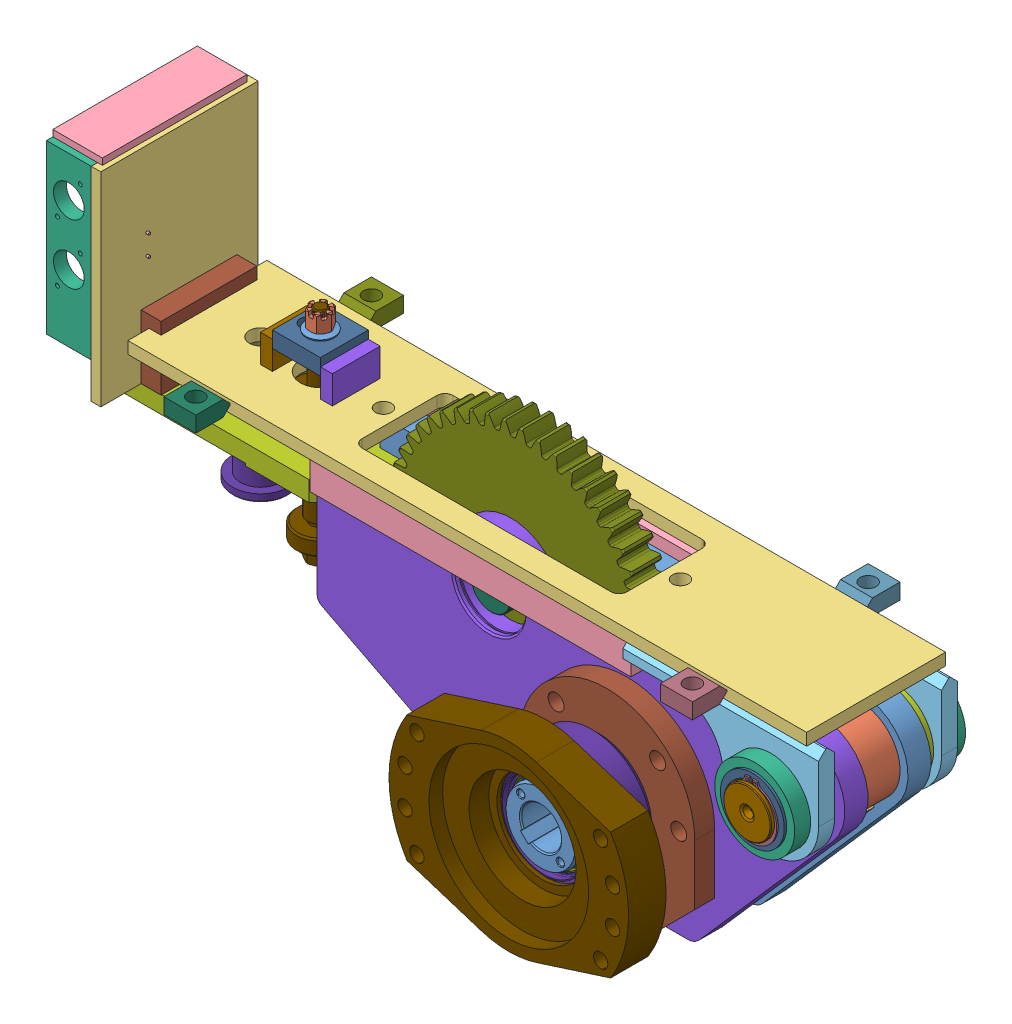
SolidWorks assembly g1_3_1_1, configuration 默认. Lengths in mm.
Overall size (943 530 331.8).
108 component instances, 72 part files, 63 mates.
Components (placement in the parent):
- g1_3_1_1_5_1-1: g1_3_1_1_5_1 [默认] at (343.3203 -95 30) x (-1 0 0) z (0 1 0) size (926 108 318.6)
  - g1_3_1_1_5-1_af1_1-1: g1_3_1_1_5-1_af1_1 [默认] at origin size (661 29 318.6)
  - g1_3_1_1_5-2_af0_1-1: g1_3_1_1_5-2_af0_1 [默认] at (-213.2 29 0) size (100 50 100)
  - g1_3_1_1_5-4_1-1: g1_3_1_1_5-4_1 [默认] at (-149.9151 54 -132.7301) x (0 1 0) z (-0.659692 0 0.751536) size (50 10 223)
  - g1_3_1_1_5-5_1-1: g1_3_1_1_5-5_1 [默认] at (20.5 54 -217) x (1 0 0) z (0 1 0) size (194 10 50)
  - g1_3_1_1_5-6_1-1: g1_3_1_1_5-6_1 [默认] at (248.4498 54 -161.5242) x (0 1 0) z (0.890083 0 0.455798) size (50 10 284)
  - g1_3_1_1_5-7_1-1: g1_3_1_1_5-7_1 [默认] at (377.8 54 -43.9) x (0 0 -1) z (0 1 0) size (87 10 50)
  - g1_3_1_1_5-9_af0_1-1: g1_3_1_1_5-9_af0_1 [默认] at (502.8 54 24.6) x (1 0 0) z (0 1 0) size (300 25 108)
  - g1_3_1_1_5-1_af0_1-1: g1_3_1_1_5-1_af0_1 [默认] at (0 79 0) size (661 29 318.6)
- g1_3_1_1_4_1-1: g1_3_1_1_4_1 [默认] at (556.5203 -95 -33.3) x (1 0 0) z (0 -1 0) size (80 234 80)
  - g1_3_1_1_4-1_1-1: g1_3_1_1_4-1_1 [默认] at origin size (60 234 60.04)
  - g1_3_1_1_4-3_1-2: g1_3_1_1_4-3_1 [默认] at (0 224.3 0) size (80 3 80)
  - g1_3_1_1_4-2_1-1: g1_3_1_1_4-2_1 [默认] at (0 174.3 0) size (72 50 72)
  - g1_3_1_1_4-2_1-2: g1_3_1_1_4-2_1 [默认] at (0 9.7 0) size (72 50 72)
  - g1_3_1_1_4-2_1-3: g1_3_1_1_4-2_1 [默认] at (0 62.7 0) size (72 50 72)
  - g1_3_1_1_4-2_1-4: g1_3_1_1_4-2_1 [默认] at (0 121.3 0) size (72 50 72)
- g1_3_1_1_2_1-1: g1_3_1_1_2_1 [默认] at (343.3203 -195.4 0) x (1 0.000801 0) z (0.000801 -1 0) size (219.6 152 245)
  - g1_3_1_1_2-1_1-1: g1_3_1_1_2-1_1 [默认] at origin size (219.6 61 245)
  - g1_3_1_1_2-2_1-1: g1_3_1_1_2-2_1 [默认] at (0 152 0) x (-0.047609 0 0.998866) z (0 1 0) size (120.16 120.16 117)
  - g1_3_1_1_2-3_1-1: g1_3_1_1_2-3_1 [默认] at (-20.1525 129 20.1525) x (0 -1 0) z (0.707107 0 0.707107) size (28 11 14)
- g1_3_1_1_3_1-1: g1_3_1_1_3_1 [默认] at (170.5203 -78.4 83.75) x (0 0 -1) z (-0.004458 0.99999 0) size (103.5 321.87 322.01)
  - g1_3_1_1_3-1_1-1: g1_3_1_1_3-1_1 [默认] at origin size (103.5 52 52)
  - _X2_60F08F6E_X0_g1_3_1_1_3-2_1-1: _X2_60F08F6E_X0_g1_3_1_1_3-2_1 [默认] at (25 0 0) x (0 0 1) z (1 0 0) size (322.01 321.87 50.08)
- g1_3_1_1_1_2-1: g1_3_1_1_1_2 [默认] at (343.3203 -195.4 123.8) x (1 0.000801 0) z (0.000801 -1 0) size (300 165.8 228)
  - g1_3_1_1_1_1_1-1: g1_3_1_1_1_1_1 [默认] at origin size (300 112 228)
    - g1_3_1_1_1_1-2_af0_1-1: g1_3_1_1_1_1-2_af0_1 [默认] at (0 50 0) size (150 65 150)
    - g1_3_1_1_1_1-3_af0_1-1: g1_3_1_1_1_1-3_af0_1 [默认] at (0 140 0) size (300 47 228)
  - g1_3_1_1_1-2_1-1: g1_3_1_1_1-2_1 [默认] at (0 122.2 0) x (0.707107 0 0.707107) z (0.707107 0 -0.707107) size (90 126 90)
  - 80_gb894_1_1-1: 80_gb894_1_1 [默认] at (-2.4 11.1 -38.1746) x (1 0 0) z (0 -1 0) size (85.83 90.87 2.5)
- g1_3_1_1_6_1-1: g1_3_1_1_6_1 [默认] at (170.5203 0 84) x (-1 0 0) z (0 0 1) size (875 200 260)
  - g1_3_1_1_6-4_af0_1-1: g1_3_1_1_6-4_af0_1 [默认] at origin size (850 15 174)
  - g1_3_1_1_6-8_1-1: g1_3_1_1_6-8_1 [默认] at (0 40 57) x (1 0 0) z (0 -1 0) size (402 20 44.8)
  - g1_3_1_1_6-8_1-2: g1_3_1_1_6-8_1 [默认] at (0 40 -77) x (1 0 0) z (0 -1 0) size (402 20 44.8)
  - g1_3_1_1_6-1_1-1: g1_3_1_1_6-1_1 [默认] at (-386 95 -87) x (1 0 0) z (0 -1 0) size (245 20 140)
  - g1_3_1_1_6-1_1-2: g1_3_1_1_6-1_1 [默认] at (-386 95 67) x (1 0 0) z (0 -1 0) size (245 20 140)
  - g1_3_1_1_6-3_1-1: g1_3_1_1_6-3_1 [默认] at (-386 95 87) x (-1 0 0) z (0 1 0) size (100 20 100)
  - g1_3_1_1_6-3_1-2: g1_3_1_1_6-3_1 [默认] at (-386 95 -107) x (-1 0 0) z (0 1 0) size (100 20 100)
  - g1_3_1_1_6-2_1-1: g1_3_1_1_6-2_1 [默认] at (-386 95 57) x (-1 0 0) z (0 1 0) size (100 10 100)
  - g1_3_1_1_6-2_1-2: g1_3_1_1_6-2_1 [默认] at (-386 95 -57) x (1 0 0) z (0 1 0) size (100 10 100)
  - g1_3_1_1_6-9_1-1: g1_3_1_1_6-9_1 [默认] at (220 -17 0) x (0 1 0) z (0 0 -1) size (35 15 60)
  - g1_3_1_1_6-9_af0_1-1: g1_3_1_1_6-9_af0_1 [默认] at (310 -17 0) x (0 1 0) z (0 0 1) size (35 15 60)
  - g1_3_1_1_6-10_1-1: g1_3_1_1_6-10_1 [默认] at (265 -45 0) size (60 20 60)
  - g1_3_1_1_6-12_af0_1-1: g1_3_1_1_6-12_af0_1 [默认] at (434 25 0.5) x (0 0 1) z (0 -1 0) size (120 25 80)
  - g1_3_1_1_6-11_af0_1-1: g1_3_1_1_6-11_af0_1 [默认] at (357 15 0) size (94 40 60)
  - g1_3_1_1_6-5_af0_1-1: g1_3_1_1_6-5_af0_1 [默认] at (-311 -5 108.5) x (0 0 -1) z (1 0 0) size (43 19.6 40)
  - g1_3_1_1_6-5_af1_1-1: g1_3_1_1_6-5_af1_1 [默认] at (-311 -5 -108.5) x (0 0 1) z (-1 0 0) size (43 19.6 40)
  - g1_3_1_1_6-5_af2_1-1: g1_3_1_1_6-5_af2_1 [默认] at (311 -5 108.5) x (0 0 -1) z (1 0 0) size (43 19.6 40)
  - g1_3_1_1_6-5_af3_1-1: g1_3_1_1_6-5_af3_1 [默认] at (311 -5 -108.5) x (0 0 1) z (-1 0 0) size (43 19.6 40)
- g1_3_1_1-1_1-1: g1_3_1_1-1_1 [默认] at (-169.4797 -45.5 84) x (1 0 -0.00083) z (-0.00083 0 -1) size (70 135 70)
- g1_3_1_1_7_1-1: g1_3_1_1_7_1 [默认] at (-94.4797 -16.0167 84) x (0 1 0) z (0.020278 0 0.999794) size (272.02 60 60)
  - g1_3_1_1_7-1_1-1: g1_3_1_1_7-1_1 [默认] at origin size (272.02 60 60)
  - a35_5_gb1972_1-1: a35_5_gb1972_1 [默认] at (39.2167 0 0) x (0 0.075145 0.997173) z (0 0.997173 -0.075145) size (35.5 7.2 35.5)
  - a35_5_gb1972_1-2: a35_5_gb1972_1 [默认] at (62.8167 0 0) x (0 -0.99777 0.066751) z (0 -0.066751 -0.99777) size (35.5 7.2 35.5)
  - m16a_gb6178_1-1: m16a_gb6178_1 [默认] at (85.8167 13.8564 0) x (0 -1 0) z (-1 0 0) size (27.71 24 20.8)
- g1_3_1_1_8_1-1: g1_3_1_1_8_1 [默认] at (-258.4797 62.5 96.5) x (0 0 -1) z (0 1 0) size (197 71 268.3)
  - g1_3_1_1_8_1_af0_1-1: g1_3_1_1_8_1_af0_1 [默认] at origin size (197 68 263)
    - g1_3_1_1_8_1-3_af1_1-1: g1_3_1_1_8_1-3_af1_1 [默认] at origin size (197 12 255)
    - g1_3_1_1_8_1-1_1-1: g1_3_1_1_8_1-1_1 [默认] at (0 37 127.5) x (1 0 0) z (0 -1 0) size (181 8 62)
    - g1_3_1_1_8_1-2_af1_1-1: g1_3_1_1_8_1-2_af1_1 [默认] at (98.5 40 22.5) x (0 1 0) z (0 0 1) size (56 16 210)
    - g1_3_1_1_8_1-2_af0_1-1: g1_3_1_1_8_1-2_af0_1 [默认] at (-98.5 40 22.5) x (0 1 0) z (0 0 -1) size (56 16 210)
    - g1_3_1_1_8_1-5_1-1: g1_3_1_1_8_1-5_1 [默认] at (0 40 -82.5) x (1 0 0) z (0 1 0) size (165 8 56)
    - g1_3_1_1_8_1-6_1-1: g1_3_1_1_8_1-6_1 [默认] at (27.5 40 -106) x (0 1 0) z (0 0 -1) size (56 6 31)
    - g1_3_1_1_8_1-6_1-2: g1_3_1_1_8_1-6_1 [默认] at (-8.5 40 -106) x (0 1 0) z (0 0 -1) size (56 6 31)
    - g1_3_1_1_8_1-4_af1_1-1: g1_3_1_1_8_1-4_af1_1 [默认] at (-10 12 5) size (105 17 85)
    - g1_3_1_1_8_1-8_af0_1-1: g1_3_1_1_8_1-8_af0_1 [默认] at (12.5 40 -127.5) x (0 1 0) z (1 0 0) size (56 6 54)
  - g1_3_1_1_8-3_1-1: g1_3_1_1_8-3_1 [默认] at (12.5 37 -32.7987) x (0 0 -1) z (0 1 0) size (229 15 15)
  - g1_3_1_1_8-6_1-1: g1_3_1_1_8-6_1 [默认] at (12.5 37 30.1) x (-1 0 0) z (0 1 0) size (26 60 26)
  - g1_3_1_1_8-5_1-1: g1_3_1_1_8-5_1 [默认] at (12.5 29 -27.5) size (60 24 20)
  - g1_3_1_1_8-9_af0_1-1: g1_3_1_1_8-9_af0_1 [默认] at (-42.5 17 5.5) size (34 10 74)
  - g1_3_1_1_8-10_1-1: g1_3_1_1_8-10_1 [默认] at (12.5 37 -127.5) x (1 0 0) z (0 1 0) size (40 2 32)
  - ya2x20x90-2_gb2089_af0_1-1: ya2x20x90-2_gb2089_af0_1 [默认] at (12.5 37 -82.5) x (0 0 -1) z (1 0 0) size (92.3 24.62 24.71)
  - 14x2_65_gb3452_1_1-1: 14x2_65_gb3452_1_1 [默认] at (12.5 37 -124.5) x (0 0 1) z (0 1 0) size (2.65 19.38 19.38)
  - 15_gb894_1_1-1: 15_gb894_1_1 [默认] at (12 29.8675 -73.9) size (17.18 18.67 1.11)
  - 8_gb93_1-1: 8_gb93_1 [默认] at (32.5 53 -27.5) x (-1 0 0) z (0 1 0) size (12.3 12.3 2.1)
  - m8x40_gb5782_1-1: m8x40_gb5782_1 [默认] at (32.5 55.1 -27.5) size (15.01 45.3 13)
  - 8_gb93_1-2: 8_gb93_1 [默认] at (-7.5 53 -27.5) x (-1 0 0) z (0 1 0) size (12.3 12.3 2.1)
  - m8x40_gb5782_1-2: m8x40_gb5782_1 [默认] at (-7.5 55.1 -27.5) size (15.01 45.3 13)
  - m3x10_gb818_1-1: m3x10_gb818_1 [默认] at (57.5 2 60.5) size (5.81 12.5 5.77)
  - m3x10_gb818_1-2: m3x10_gb818_1 [默认] at (57.5 2 100.5) size (5.81 12.5 5.77)
  - m3x10_gb818_1-3: m3x10_gb818_1 [默认] at (-17.5 2 100.5) size (5.81 12.5 5.77)
  - m3x10_gb818_1-4: m3x10_gb818_1 [默认] at (-57.5 2 100.5) size (5.81 12.5 5.77)
  - m3x30_gb818_1-1: m3x30_gb818_1 [默认] at (-40.5 -3 7.5) size (5.81 32.5 5.77)
  - m3x30_gb818_1-2: m3x30_gb818_1 [默认] at (-40.5 -3 32.9) size (5.81 32.5 5.77)
  - 6_gb93_1-9: 6_gb93_1 [默认] at (-52.5 28.6 -17.5) x (1 0 0) z (0 -1 0) size (9.3 9.3 1.6)
  - m6x20_gb5783_1-9: m6x20_gb5783_1 [默认] at (-52.5 28.6 -17.5) size (11.55 24 10)
  - 6_gb93_1-10: 6_gb93_1 [默认] at (-32.5 28.6 -17.5) x (1 0 0) z (0 -1 0) size (9.3 9.3 1.6)
  - m6x20_gb5783_1-10: m6x20_gb5783_1 [默认] at (-32.5 28.6 -17.5) size (11.55 24 10)
  - 5x14_gb119_2_1-1: 5x14_gb119_2_1 [默认] at (-42.5 27 -3.5) size (5 14 5)
  - m3x6_gb818_1-1: m3x6_gb818_1 [默认] at (27.5 37 -123.5) x (1 0 0) z (0 1 0) size (5.81 8.5 5.77)
  - m3x6_gb818_1-2: m3x6_gb818_1 [默认] at (-2.5 37 -123.5) x (1 0 0) z (0 1 0) size (5.81 8.5 5.77)
- _X2_57AB5708_X0_16_gb93_1-9: _X2_57AB5708_X0_16_gb93_1 [默认] at (-270.4797 -50 44) x (0 0.924225 0.381849) z (-1 0 0) size (24.4 24.4 4.1)
- _X2_87BA6813_X0_m16x35_gb5783_10_1-1: _X2_87BA6813_X0_m16x35_gb5783_10_1 [默认] at (-274.5797 -50 44) x (0 -0.866025 -0.5) z (0 0.5 -0.866025) size (27.71 45 24)
- _X2_57AB5708_X0_16_gb93_1-10: _X2_57AB5708_X0_16_gb93_1 [默认] at (-270.4797 -50 124) x (0 0.924225 0.381849) z (-1 0 0) size (24.4 24.4 4.1)
- _X2_87BA6813_X0_m16x35_gb5783_10_1-2: _X2_87BA6813_X0_m16x35_gb5783_10_1 [默认] at (-274.5797 -50 124) x (0 -0.866025 -0.5) z (0 0.5 -0.866025) size (27.71 45 24)
- g1_3_1_1_1_1-1_af0_1-1: g1_3_1_1_1_1-1_af0_1 [默认] at (343.3203 -195.4 113) x (1 0 0) z (0 -1 0) size (220 42 245)
- g1_3_1_1_7-2_1-1: g1_3_1_1_7-2_1 [默认] at (-126.2339 -95.4 83.9778) x (1 0 0.0007) z (0 -1 0) size (63.51 55 25)
- g1_3_1_1_4-3_1-2: g1_3_1_1_4-3_1 [默认] at (556.5203 -95 -23.6) x (-0.923728 -0.383049 0) z (0.383049 -0.923728 0) size (80 3 80)
- 60_gb894_1_1-2: 60_gb894_1_1 [默认] at (558.4703 -66.5668 -28.6) x (-1 0 0) z (0 0 1) size (65.16 69.76 2)
- 60_gb894_1_1-3: 60_gb894_1_1 [默认] at (558.4703 -66.5668 194) x (-1 0 0) z (0 0 1) size (65.16 69.76 2)
- 16x10x45_gb1096_1-2: 16x10x45_gb1096_1 [默认] at (170.4089 -53.4002 83.25) x (0 0 -1) z (0.004458 -0.99999 0) size (45 16 10)
- g1_3_1_1_1-1_1-1: g1_3_1_1_1-1_1 [默认] at (343.3203 -195.4 210.3) x (0 0 -1) z (0.990882 0.134732 0) size (20 110 110)
- b90x110x12_gb9877_1_rubber_1-1: b90x110x12_gb9877_1_rubber_1 [默认] at (343.3203 -195.4 194.3) x (1 0 0) z (0 -1 0) size (108.6 12 108.6)
- b90x110x12_gb9877_1_rubber_1-2: b90x110x12_gb9877_1_rubber_1 [默认] at (343.3203 -195.4 226.3) x (1 0 0) z (0 1 0) size (108.6 12 108.6)
- b90x110x12_gb9877_1_frame_1-1: b90x110x12_gb9877_1_frame_1 [默认] at (343.3203 -195.4 232.3) x (-0.923728 -0.383049 0) z (-0.383049 0.923728 0) size (107.2 9.5 107.2)
- b90x110x12_gb9877_1_frame_1-2: b90x110x12_gb9877_1_frame_1 [默认] at (343.3203 -195.4 188.3) x (0.999991 -0.004354 0) z (0.004354 0.999991 0) size (107.2 9.5 107.2)
- g1_3_1_1_5-8_1-1: g1_3_1_1_5-8_1 [默认] at (-94.4797 -70.4 84) x (0.999971 0 -0.007558) z (0.007558 0 0.999971) size (60 50 60)
- 15_gb894_1_1-1: 15_gb894_1_1 [默认] at (-302.5811 152.7 83.1678) x (-0.046648 0 0.998911) z (0 1 0) size (17.18 18.67 1.11)
- 15_gb894_1_1-2: 15_gb894_1_1 [默认] at (-302.6048 91.5 83.404) x (-0.01346 0 0.999909) z (0 1 0) size (17.18 18.67 1.11)
Mates (geometry in assembly coordinates):
- 重合1: coincident anti-aligned: plane of g1_3_1_1_2_1-1/g1_3_1_1_2-3_1-1 through (318.2302 -210.6229 129) normal (-0.707673 0.70654 0); plane of g1_3_1_1_1_2-1/g1_3_1_1_1-2_1-1 through (318.0182 -210.8352 246) normal (0.707673 -0.70654 0)
- 重合2: coincident anti-aligned: plane of g1_3_1_1_2_1-1/g1_3_1_1_2-2_1-1 through (343.3203 -195.4 120) normal (0 0 1); plane of g1_3_1_1_1_2-1/g1_3_1_1_1-2_1-1 through (343.3203 -195.4 120) normal (0 0 -1)
- 同心3: concentric aligned: cylinder of g1_3_1_1_2_1-1/g1_3_1_1_2-2_1-1 through (343.3203 -195.4 29.15) axis (0 0 1) radius 25; cylinder of g1_3_1_1_1_2-1/g1_3_1_1_1-2_1-1 through (343.3203 -195.4 246) axis (0 0 1) radius 25
- 同心9: concentric anti-aligned: cylinder of g1_3_1_1_8_1-1/g1_3_1_1_8_1_af0_1-1/g1_3_1_1_8_1-3_af1_1-1 through (-270.4797 -50 124) axis (1 0 0) radius 8.5; cylinder of _X2_87BA6813_X0_m16x35_gb5783_10_1-2 through (-237.8297 -50 124) axis (-1 0 0) radius 8
- 同心12: concentric anti-aligned: cylinder of g1_3_1_1_6_1-1/g1_3_1_1_6-12_af0_1-1 through (-214.9634 -50 44) axis (1 0 0) radius 7; cylinder of _X2_87BA6813_X0_m16x35_gb5783_10_1-1 through (-237.8297 -50 44) axis (-1 0 0) radius 8
- 同心13: concentric aligned: cylinder of _X2_57AB5708_X0_16_gb93_1-10 through (-270.4797 -50 124) axis (-1 0 0) radius 8.1; cylinder of _X2_87BA6813_X0_m16x35_gb5783_10_1-2 through (-237.8297 -50 124) axis (-1 0 0) radius 8
- 同心14: concentric aligned: cylinder of _X2_57AB5708_X0_16_gb93_1-9 through (-270.4797 -50 44) axis (-1 0 0) radius 8.1; cylinder of _X2_87BA6813_X0_m16x35_gb5783_10_1-1 through (-237.8297 -50 44) axis (-1 0 0) radius 8
- 重合3: coincident anti-aligned: plane of _X2_57AB5708_X0_16_gb93_1-9 through (-274.5797 -50 44) normal (-1 0 0); plane of _X2_87BA6813_X0_m16x35_gb5783_10_1-1 through (-274.5797 -50 44) normal (1 0 0)
- 重合4: coincident anti-aligned: plane of _X2_57AB5708_X0_16_gb93_1-10 through (-274.5797 -50 124) normal (-1 0 0); plane of _X2_87BA6813_X0_m16x35_gb5783_10_1-2 through (-274.5797 -50 124) normal (1 0 0)
- 同心15: concentric aligned: cylinder of g1_3_1_1_8_1-1/g1_3_1_1_8_1_af0_1-1/g1_3_1_1_8_1-3_af1_1-1 through (-270.4797 -50 44) axis (-1 0 0) radius 8.5; cylinder of _X2_87BA6813_X0_m16x35_gb5783_10_1-1 through (-237.8297 -50 44) axis (-1 0 0) radius 8
- 同心18: concentric aligned: cylinder of g1_3_1_1_6_1-1/g1_3_1_1_6-11_af0_1-1 through (-169.4797 71.0063 84) axis (0 -1 0) radius 14; cylinder of g1_3_1_1-1_1-1 through (-169.4797 -19.25 84) axis (0 -1 0) radius 15
- 同心20: concentric anti-aligned: cylinder of g1_3_1_1_5_1-1/g1_3_1_1_5-9_af0_1-1 through (-169.4797 -95.4 84) axis (0 1 0) radius 27; cylinder of g1_3_1_1-1_1-1 through (-169.4797 -50.5 84) axis (0 -1 0) radius 25
- 重合10: coincident anti-aligned: plane of g1_3_1_1_8_1-1/g1_3_1_1_8_1_af0_1-1/g1_3_1_1_8_1-3_af1_1-1 through (-270.4797 62.5 96.5) normal (-1 0 0); plane of _X2_57AB5708_X0_16_gb93_1-9 through (-270.4797 -50 44) normal (1 0 0)
- 重合12: coincident anti-aligned: plane of g1_3_1_1_8_1-1/g1_3_1_1_8_1_af0_1-1/g1_3_1_1_8_1-3_af1_1-1 through (-270.4797 62.5 96.5) normal (-1 0 0); plane of _X2_57AB5708_X0_16_gb93_1-10 through (-270.4797 -50 124) normal (1 0 0)
- 重合13: coincident anti-aligned: plane of g1_3_1_1_6_1-1/g1_3_1_1_6-12_af0_1-1 through (-258.4797 0 84) normal (-1 0 0); plane of g1_3_1_1_8_1-1/g1_3_1_1_8_1_af0_1-1/g1_3_1_1_8_1-3_af1_1-1 through (-258.4797 62.5 96.5) normal (1 0 0)
- 同心23: concentric aligned: cylinder of g1_3_1_1_5_1-1/g1_3_1_1_5-1_af1_1-1 through (556.5203 -95 30) axis (0 0 1) radius 36; cylinder of g1_3_1_1_6_1-1/g1_3_1_1_6-3_1-2 through (556.5203 -95 -23) axis (0 0 1) radius 36
- 同心24: concentric aligned: cylinder of g1_3_1_1_4_1-1/g1_3_1_1_4-2_1-2 through (556.5203 -95 -23.6) axis (0 0 1) radius 36; cylinder of g1_3_1_1_6_1-1/g1_3_1_1_6-3_1-2 through (556.5203 -95 -23) axis (0 0 1) radius 36
- 重合14: coincident anti-aligned: plane of g1_3_1_1_4_1-1/g1_3_1_1_4-3_1-2 through (556.5203 -95 191) normal (0 0 -1); plane of g1_3_1_1_6_1-1/g1_3_1_1_6-3_1-1 through (556.5203 -95 191) normal (0 0 1)
- 同心25: concentric aligned: cylinder of g1_3_1_1_5_1-1/g1_3_1_1_5-1_af1_1-1 through (170.5203 -78.4 30) axis (0 0 1) radius 45; cylinder of g1_3_1_1_3_1-1/g1_3_1_1_3-1_1-1 through (170.5203 -78.4 26.825) axis (0 0 1) radius 25
- 同心26: concentric aligned: cylinder of g1_3_1_1_5_1-1/g1_3_1_1_5-1_af1_1-1 through (343.3203 -195.4 30) axis (0 0 1) radius 75; cylinder of g1_3_1_1_2_1-1/g1_3_1_1_2-1_1-1 through (343.3203 -195.4 30) axis (0 0 1) radius 75
- 重合16: coincident anti-aligned: plane of g1_3_1_1_5_1-1/g1_3_1_1_5-1_af1_1-1 through (343.3203 -95 30) normal (0 0 -1); plane of g1_3_1_1_2_1-1/g1_3_1_1_2-1_1-1 through (343.3203 -195.4 30) normal (0 0 1)
- 重合17: coincident anti-aligned: plane of g1_3_1_1_5_1-1/g1_3_1_1_5-1_af1_1-1; plane of ? through (523.5275 -270.9624 278.2595) normal (0 -1 0)
- 重合19: coincident aligned: plane of g1_3_1_1_5_1-1/g1_3_1_1_5-1_af0_1-1 through (170.5203 -78.4 128.8) normal (0 0 1); plane of g1_3_1_1_3_1-1/g1_3_1_1_3-1_1-1 through (170.5203 -78.4 128.8) normal (0 0 1)
- 重合28: coincident anti-aligned: plane of g1_3_1_1_2_1-1/g1_3_1_1_2-1_1-1 through (343.3203 -195.4 0) normal (0 0 -1); plane of assembly through (0 0 0) normal (0 0 1)
- 重合31: coincident aligned: plane of g1_3_1_1_6_1-1/g1_3_1_1_6-4_af0_1-1 through (170.5203 0 84) normal (0 1 0); plane of assembly through (0 0 0) normal (0 1 0)
- 同心28: concentric aligned: cylinder of g1_3_1_1_6_1-1/g1_3_1_1_6-12_af0_1-1 through (-214.9634 -50 124) axis (-1 0 0) radius 7; cylinder of _X2_87BA6813_X0_m16x35_gb5783_10_1-2 through (-237.8297 -50 124) axis (-1 0 0) radius 8
- 同心29: concentric aligned: cylinder of g1_3_1_1_5_1-1/g1_3_1_1_5-1_af0_1-1 through (343.3203 -195.4 109) axis (0 0 1) radius 75; cylinder of g1_3_1_1_1_1-1_af0_1-1 through (343.3203 -195.4 -384.4109) axis (0 0 1) radius 75
- 同心30: concentric aligned: cylinder of g1_3_1_1_5_1-1/g1_3_1_1_5-1_af0_1-1 through (279.7203 -131.8 108.5324) axis (0 0 1) radius 5.1; cylinder of g1_3_1_1_1_1-1_af0_1-1 through (279.7203 -131.8 163) axis (0 0 1) radius 10
- 重合33: coincident anti-aligned: plane of g1_3_1_1_5_1-1/g1_3_1_1_5-1_af0_1-1 through (343.3203 -95 138) normal (0 0 1); plane of g1_3_1_1_1_1-1_af0_1-1 through (343.3203 -195.4 138) normal (0 0 -1)
- 平行2: parallel aligned: plane of ? through (593.4401 -66.5668 194.2) normal (1 0 0); plane of g1_3_1_1_6_1-1/g1_3_1_1_6-1_1-2 through (595.2275 -95 151) normal (1 0 0)
- 重合37: coincident anti-aligned: plane of g1_3_1_1_6_1-1/g1_3_1_1_6-11_af0_1-1 through (-139.4797 -50.5 114) normal (0 -1 0); plane of g1_3_1_1-1_1-1 through (-169.4797 -50.5 84) normal (0 1 0)
- 平行5: parallel anti-aligned: plane of g1_3_1_1_8_1-1/g1_3_1_1_8_1_af0_1-1/g1_3_1_1_8_1-5_1-1 through (-298.4797 -28 96.5) normal (0 -1 0); plane of _X2_87BA6813_X0_m16x35_gb5783_10_1-2 through (-274.5797 -38 130.9282) normal (0 1 0)
- 平行6: parallel anti-aligned: plane of g1_3_1_1_8_1-1/g1_3_1_1_8_1_af0_1-1/g1_3_1_1_8_1-5_1-1 through (-298.4797 -28 96.5) normal (0 -1 0); plane of _X2_87BA6813_X0_m16x35_gb5783_10_1-1 through (-274.5797 -38 50.9282) normal (0 1 0)
- 同心33: concentric anti-aligned: cylinder of g1_3_1_1_6_1-1/g1_3_1_1_6-10_1-1 through (-94.4797 45 84) axis (0 -1 0) radius 10; cylinder of g1_3_1_1_7_1-1/g1_3_1_1_7-1_1-1 through (-94.4797 -471.3188 84) axis (0 1 0) radius 8.9
- 同心34: concentric anti-aligned: cylinder of g1_3_1_1_7_1-1/g1_3_1_1_7-1_1-1 through (-94.4797 -471.3188 84) axis (0 1 0) radius 16; cylinder of g1_3_1_1_7-2_1-1 through (-94.4797 -95.4 84) axis (0 -1 0) radius 16.376
- 重合38: coincident anti-aligned: plane of ? through (-109.2633 -95.4 84) normal (0 -1 0); plane of g1_3_1_1_7-2_1-1 through (-141.0175 -95.4 83.9778) normal (0 1 0)
- 距离1: distance = 4 mm anti-aligned: plane of g1_3_1_1_7_1-1/g1_3_1_1_7-1_1-1 through (-94.4797 21 84) normal (0 1 0); plane of g1_3_1_1_6_1-1/g1_3_1_1_6-10_1-1 through (-94.4797 25 84) normal (0 -1 0)
- 重合40: coincident anti-aligned: plane of g1_3_1_1_4_1-1/g1_3_1_1_4-2_1-2 through (556.5203 -95 -23.6) normal (0 0 -1); plane of g1_3_1_1_4-3_1-2 through (556.5203 -95 -23.6) normal (0 0 1)
- 同心35: concentric anti-aligned: cylinder of g1_3_1_1_4_1-1/g1_3_1_1_4-1_1-1 through (556.5203 -95 -33.3) axis (0 0 1) radius 30; cylinder of g1_3_1_1_4-3_1-2 through (556.5203 -95 -23.6) axis (0 0 -1) radius 30.5
- 同心36: concentric aligned: cylinder of g1_3_1_1_4_1-1/g1_3_1_1_4-1_1-1 through (556.5203 -95 450.0941) axis (0 0 1) radius 28.5; cylinder of 60_gb894_1_1-2 through (556.5203 -95 -28.6) axis (0 0 1) radius 28.5
- 重合41: coincident anti-aligned: plane of g1_3_1_1_4-3_1-2 through (556.5203 -95 -26.6) normal (0 0 -1); plane of 60_gb894_1_1-2 through (558.4703 -66.5668 -26.6) normal (0 0 1)
- 重合42: coincident anti-aligned: plane of g1_3_1_1_4_1-1/g1_3_1_1_4-3_1-2 through (556.5203 -95 194) normal (0 0 1); plane of 60_gb894_1_1-3 through (558.4703 -66.5668 194) normal (0 0 -1)
- 同心37: concentric aligned: cylinder of g1_3_1_1_4_1-1/g1_3_1_1_4-1_1-1 through (556.5203 -95 -282.6941) axis (0 0 1) radius 28.5; cylinder of 60_gb894_1_1-3 through (556.5203 -95 194) axis (0 0 1) radius 28.5
- 重合51: coincident anti-aligned: plane of g1_3_1_1_3_1-1/g1_3_1_1_3-1_1-1 through (170.4312 -58.4002 83.75) normal (-0.004458 0.99999 0); plane of 16x10x45_gb1096_1-2 through (170.4312 -58.4002 83.25) normal (0.004458 -0.99999 0)
- 同心39: concentric aligned: cylinder of g1_3_1_1_3_1-1/g1_3_1_1_3-1_1-1 through (170.4044 -52.4003 68.75) axis (-0.004458 0.99999 0) radius 8; cylinder of 16x10x45_gb1096_1-2 through (170.4312 -58.4158 68.75) axis (-0.004458 0.99999 0) radius 8
- 重合52: coincident anti-aligned: plane of g1_3_1_1_3_1-1/g1_3_1_1_3-1_1-1 through (178.4043 -52.3646 98.75) normal (-0.99999 -0.004458 0); plane of 16x10x45_gb1096_1-2 through (178.3865 -48.3646 60.75) normal (0.99999 0.004458 0)
- 重合53: coincident: plane of ? through (335.0708 -180.6788 216.0533) normal (0 0 1); plane of g1_3_1_1_1-1_1-1 through (322.0275 -195.4 213.1) normal (0 0 1)
- 同心40: concentric anti-aligned: cylinder of g1_3_1_1_1_2-1/g1_3_1_1_1-2_1-1 through (343.3203 -195.4 246) axis (0 0 -1) radius 45; cylinder of g1_3_1_1_1-1_1-1 through (343.3203 -195.4 199.3) axis (0 0 1) radius 49
- 同心44: concentric anti-aligned: cylinder of g1_3_1_1_1-1_1-1 through (343.3203 -195.4 199.3) axis (0 0 1) radius 53; cylinder of b90x110x12_gb9877_1_rubber_1-2 through (343.3203 -195.4 232.9) axis (0 0 -1) radius 54.2995
- 重合59: coincident anti-aligned: plane of g1_3_1_1_1-1_1-1 through (343.3203 -195.4 220.3) normal (0 0 1); plane of b90x110x12_gb9877_1_rubber_1-2 through (343.3203 -195.4 220.3) normal (0 0 -1)
- 重合60: coincident anti-aligned: plane of b90x110x12_gb9877_1_rubber_1-2 through (343.3203 -195.4 232.3) normal (0 0 1); plane of b90x110x12_gb9877_1_frame_1-1 through (343.3203 -195.4 232.3) normal (0 0 -1)
- 重合61: coincident anti-aligned: plane of g1_3_1_1_1-1_1-1 through (343.3203 -195.4 200.3) normal (0 0 -1); plane of b90x110x12_gb9877_1_rubber_1-1 through (343.3203 -195.4 200.3) normal (0 0 1)
- 同心45: concentric aligned: cylinder of g1_3_1_1_1-1_1-1 through (343.3203 -195.4 199.3) axis (0 0 1) radius 53; cylinder of b90x110x12_gb9877_1_rubber_1-1 through (343.3203 -195.4 187.7) axis (0 0 1) radius 54.2995
- 重合62: coincident anti-aligned: plane of b90x110x12_gb9877_1_rubber_1-1 through (343.3203 -195.4 188.3) normal (0 0 -1); plane of b90x110x12_gb9877_1_frame_1-2 through (343.3203 -195.4 188.3) normal (0 0 1)
- 同心46: concentric anti-aligned: cylinder of b90x110x12_gb9877_1_rubber_1-1 through (343.3203 -195.4 187.7) axis (0 0 1) radius 54.2995; cylinder of b90x110x12_gb9877_1_frame_1-2 through (343.3203 -195.4 188.775) axis (0 0 -1) radius 52.3
- 同心47: concentric anti-aligned: cylinder of g1_3_1_1_1-1_1-1 through (343.3203 -195.4 199.3) axis (0 0 1) radius 49; circle of b90x110x12_gb9877_1_frame_1-1
- 重合63: coincident anti-aligned: plane of g1_3_1_1_1_2-1/g1_3_1_1_1_1_1-1/g1_3_1_1_1_1-2_af0_1-1 through (343.3203 -195.4 178.8) normal (0 0 1); plane of b90x110x12_gb9877_1_frame_1-2 through (343.3203 -195.4 178.8) normal (0 0 -1)
- 同心48: concentric aligned: cylinder of g1_3_1_1_7_1-1/g1_3_1_1_7-1_1-1 through (-94.4797 -471.3188 84) axis (0 1 0) radius 12; cylinder of g1_3_1_1_5-8_1-1 through (-94.4797 -70.4 84) axis (0 1 0) radius 30
- 重合66: coincident anti-aligned: plane of g1_3_1_1_5_1-1/g1_3_1_1_5-9_af0_1-1 through (-159.4797 -70.4 84) normal (0 1 0); plane of g1_3_1_1_5-8_1-1 through (-94.4797 -70.4 84) normal (0 -1 0)
- 同心49: concentric anti-aligned: cylinder of g1_3_1_1_8_1-1/g1_3_1_1_8-3_1-1 through (-295.4797 413.083 84) axis (0 -1 0) radius 7; cylinder of 15_gb894_1_1-1 through (-295.4797 152.7 84) axis (0 1 0) radius 7.15
- 重合67: coincident anti-aligned: plane of g1_3_1_1_8_1-1/g1_3_1_1_8-3_1-1 through (-295.4797 153.7 84) normal (0 -1 0); plane of 15_gb894_1_1-1 through (-302.5811 153.7 83.1678) normal (0 1 0)
- 同心50: concentric anti-aligned: cylinder of g1_3_1_1_8_1-1/g1_3_1_1_8-3_1-1 through (-295.4797 413.083 84) axis (0 -1 0) radius 7; cylinder of 15_gb894_1_1-2 through (-295.4797 91.5 84) axis (0 1 0) radius 7.15
- 重合68: coincident anti-aligned: plane of g1_3_1_1_8_1-1/g1_3_1_1_8-3_1-1 through (-295.4797 91.5 84) normal (0 1 0); plane of 15_gb894_1_1-2 through (-302.6048 91.5 83.404) normal (0 -1 0)
